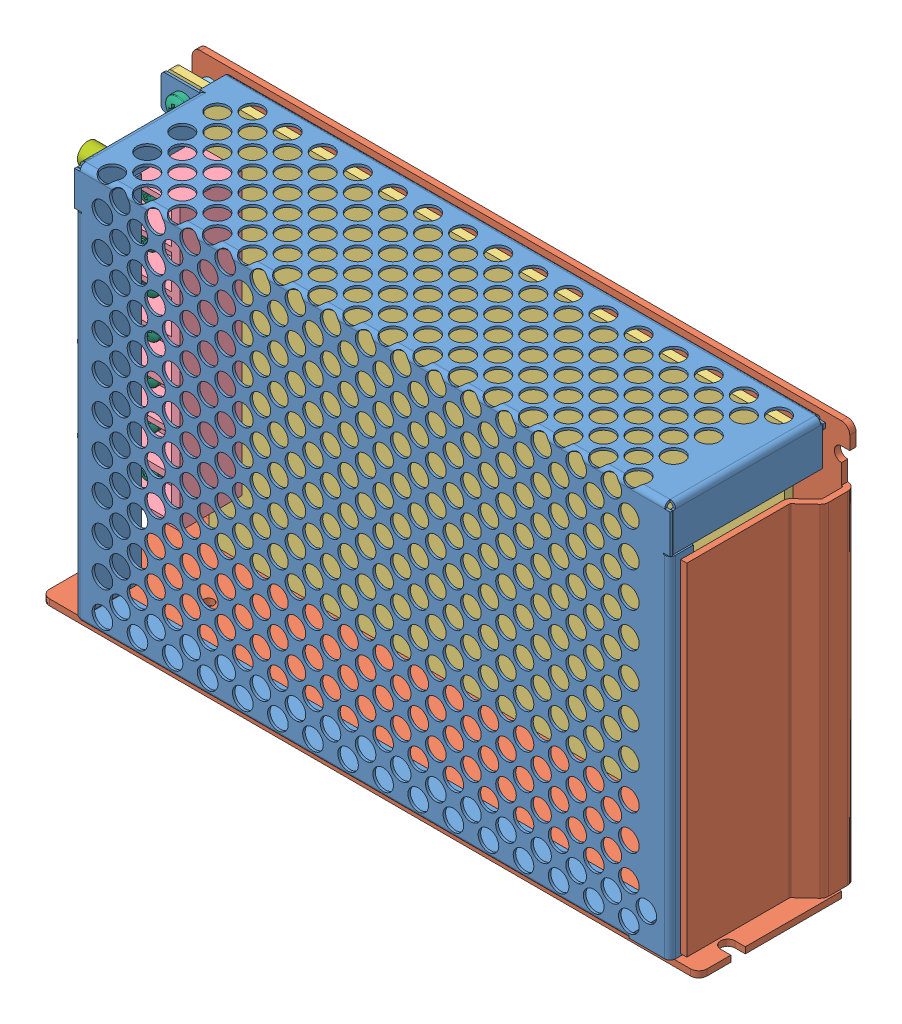
SolidWorks assembly MeanWell_RS-100, configuration Default. Lengths in mm.
Overall size (168.18 98 39.02).
18 component instances, 10 part files, 22 mates.
Components (placement in the parent):
- GRATE^MeanWell_RS-100-1: GRATE^MeanWell_RS-100 [Default] at (81.1 67.5 38.4225) x (0 1 0) z (1 0 0) size (95.52 37.52 154) (virtual)
- PLATE^MeanWell_RS-100-1: PLATE^MeanWell_RS-100 [Default] at origin size (159 98 38) (virtual)
- PCB^MeanWell_RS-100-1: PCB^MeanWell_RS-100 [Default] at (1.2532 0 0) size (149.23 94.42 2) (virtual)
- BLOCK^MeanWell_RS-100-1: BLOCK^MeanWell_RS-100 [Default] at (1.2532 0 0) size (18 68.05 15) (virtual)
- Part5^MeanWell_RS-100-1: Part5^MeanWell_RS-100 [Default] at (0 0 1.5) size (5 5 4) (virtual)
- pan head cross recess screw_iso-1: pan head cross recess screw_iso [ISO 7045 - M3 x 8 - Z - 8N] at (4.5 91 10.5) x (0 0 -1) z (0.977005 0.213215 0) size (10.35 5.6 5.6)
- pan head cross recess screw_iso-2: pan head cross recess screw_iso [ISO 7045 - M3 x 8 - Z - 8N] at (5.9804 78.9388 19.0526) x (0 0 -1) z (0.977005 0.213215 0) size (10.35 5.6 5.6)
- pan head cross recess screw_iso-3: pan head cross recess screw_iso [ISO 7045 - M3 x 8 - Z - 8N] at (5.9804 69.2602 19.1612) x (0 0 -1) z (0.977005 0.213215 0) size (10.35 5.6 5.6)
- pan head cross recess screw_iso-4: pan head cross recess screw_iso [ISO 7045 - M3 x 8 - Z - 8N] at (6.1839 59.8468 19.2114) x (0 0 -1) z (0.977005 0.213215 0) size (10.35 5.6 5.6)
- pan head cross recess screw_iso-5: pan head cross recess screw_iso [ISO 7045 - M3 x 8 - Z - 8N] at (6.1839 50.4574 19.0585) x (0 0 -1) z (0.977005 0.213215 0) size (10.35 5.6 5.6)
- pan head cross recess screw_iso-6: pan head cross recess screw_iso [ISO 7045 - M3 x 8 - Z - 8N] at (6.0089 40.8687 19.1627) x (0 0 -1) z (0.977005 0.213215 0) size (10.35 5.6 5.6)
- pan head cross recess screw_iso-7: pan head cross recess screw_iso [ISO 7045 - M3 x 8 - Z - 8N] at (6.0094 31.4444 19.1501) x (0 0 -1) z (0.977005 0.213215 0) size (10.35 5.6 5.6)
- pan head cross recess screw_iso-8: pan head cross recess screw_iso [ISO 7045 - M3 x 8 - Z - 8N] at (6.0094 21.1124 19.2488) x (0 0 -1) z (0.977005 0.213215 0) size (10.35 5.6 5.6)
- Insulated Ring Terminal ID 3mm-Red-11: Insulated Ring Terminal ID 3mm-Red [Black] at (5.9804 78.9388 15.75) x (0.000176 1 0) z (1 -0.000176 0) size (5.54 5.16 17.93)
- Insulated Ring Terminal ID 3mm-White-7: Insulated Ring Terminal ID 3mm-White [Default] at (5.9804 69.2602 15.75) x (0.000176 1 0) z (1 -0.000176 0) size (5.54 5.16 17.93) (hidden)
- Insulated Ring Terminal ID 3mm-Green-8: Insulated Ring Terminal ID 3mm-Green [Default] at (6.1839 59.8468 15.75) x (0.000176 1 0) z (1 -0.000176 0) size (5.54 5.16 31.83)
- Insulated Ring Terminal ID 3mm-9: Insulated Ring Terminal ID 3mm [Default] at (6.0089 40.8687 15.75) x (0.000176 1 0) z (1 -0.000176 0) size (5.54 5.16 17.93)
- Insulated Ring Terminal ID 3mm-Red-10: Insulated Ring Terminal ID 3mm-Red [Black] at (6.0094 21.1124 15.75) x (0.000176 1 0) z (1 -0.000176 0) size (5.54 5.16 17.93)
Mates (geometry in assembly coordinates):
- Coincident2: coincident anti-aligned: plane of Copy of GRATE^MeanWell_RS-100-1 through (122.644 95.1725 1.5) normal (0 0 -1); plane of PLATE-1 through (156.5 84.5 1.5) normal (0 0 1)
- Coincident3: coincident anti-aligned: plane of Copy of GRATE^MeanWell_RS-100-1 through (153.1 43.7612 35.5542) normal (1 0 0); plane of PLATE-1 through (153.1 2.5 12.0158) normal (-1 0 0)
- Coincident4: coincident anti-aligned: plane of Copy of GRATE^MeanWell_RS-100-1 through (117.644 1.5 33.3725) normal (0 -1 0); plane of PLATE-1 through (78.25 1.5 -47.7633) normal (0 1 0)
- Coincident5: coincident aligned: plane of Copy of PCB^MeanWell_RS-100-1 through (0.0262 59.5225 13.5) normal (-1 0 0); plane of BLOCK-1 through (0.0262 59.5225 13.5) normal (-1 0 0)
- Coincident6: coincident anti-aligned: plane of Copy of GRATE^MeanWell_RS-100-1 through (3.7317 91.5542 7.5) normal (0 0 -1); plane of PCB-1 through (95.6262 49.2125 7.5) normal (0 0 1)
- InPlace1: in place: plane of PLATE^MeanWell_RS-100-1 through (156.5 84.5 1.5) normal (0 0 1); plane of Part5^MeanWell_RS-100-1 through (0 0 1.5) normal (0 0 1); moOrthogonalPlaneRef_w of PLATE^MeanWell_RS-100-1 through (156.5 84.5 1.5) normal (0 0 1); plane of Part5^MeanWell_RS-100-1 through (0 0 1.5) normal (0 1 0); plane of PLATE^MeanWell_RS-100-1 through (156.5 84.5 1.5) normal (0 0 1); plane of Part5^MeanWell_RS-100-1 through (0 0 1.5) normal (1 0 0); plane of PLATE^MeanWell_RS-100-1 through (156.5 84.5 1.5) normal (0 0 1); unknown of Part5^MeanWell_RS-100-1
- Coincident7: coincident aligned: plane of ?; plane of ?
- Coincident8: coincident aligned: moOrthogonalPlaneRef_w of Copy of PLATE^MeanWell_RS-100-1 through (0 0 1.5) normal (0 1 0); plane of Part5^MeanWell_RS-100-1 through (0 0 1.5) normal (0 1 0)
- Coincident9: coincident anti-aligned: moOrthogonalPlaneRef_w of Copy of PLATE^MeanWell_RS-100-1 through (0 0 1.5) normal (-1 0 0); plane of Part5^MeanWell_RS-100-1 through (0 0 1.5) normal (1 0 0)
- Concentric1: concentric anti-aligned: cylinder of Part5^MeanWell_RS-100-1 through (4.5 91 5.5) axis (0 0 -1) radius 2.5; cylinder of pan head cross recess screw_iso-1 through (4.5 91 35.9) axis (0 0 1) radius 1.5
- Coincident10: coincident anti-aligned: plane of Copy of GRATE^MeanWell_RS-100-1 through (3.7317 91.5542 8.1) normal (0 0 1); plane of pan head cross recess screw_iso-1 through (4.1802 92.4655 8.1) normal (0 0 -1)
- Coincident11: coincident anti-aligned: plane of ? through (8.0262 78.5975 15.75) normal (0 0 1); plane of ? through (-4.0516 78.8869 15.75) normal (0 0 -1)
- Coincident12: coincident anti-aligned: plane of Copy of BLOCK^MeanWell_RS-100-1 through (8.0262 69.1475 15.75) normal (0 0 1); plane of Insulated Ring Terminal ID 3mm-Red-11 through (8.8673 76.0572 15.75) normal (0 0 -1)
- Concentric2: concentric aligned: cylinder of pan head cross recess screw_iso-2 through (5.9804 78.9388 44.4526) axis (0 0 1) radius 1.5; cylinder of Insulated Ring Terminal ID 3mm-Red-11 through (5.9804 78.9388 15.75) axis (0 0 1) radius 1.8415
- Coincident14: coincident anti-aligned: plane of Copy of BLOCK^MeanWell_RS-100-1 through (8.0262 69.1475 15.75) normal (0 0 1); plane of Insulated Ring Terminal ID 3mm-White-7 through (8.8673 66.3785 15.75) normal (0 0 -1)
- Coincident15: coincident anti-aligned: plane of Copy of BLOCK^MeanWell_RS-100-1 through (8.0262 59.6975 15.75) normal (0 0 1); plane of Insulated Ring Terminal ID 3mm-Green-8 through (9.0709 56.9652 15.75) normal (0 0 -1)
- Coincident16: coincident anti-aligned: plane of Copy of BLOCK^MeanWell_RS-100-1 through (8.0262 40.7975 15.75) normal (0 0 1); plane of Insulated Ring Terminal ID 3mm-9 through (8.8959 37.9871 15.75) normal (0 0 -1)
- Concentric3: concentric aligned: cylinder of pan head cross recess screw_iso-6 through (6.0089 40.8687 44.5627) axis (0 0 1) radius 1.5; cylinder of Insulated Ring Terminal ID 3mm-9 through (6.0089 40.8687 15.75) axis (0 0 1) radius 1.8415
- Concentric4: concentric aligned: cylinder of pan head cross recess screw_iso-4 through (6.1839 59.8468 44.6114) axis (0 0 1) radius 1.5; cylinder of Insulated Ring Terminal ID 3mm-Green-8 through (6.1839 59.8468 15.75) axis (0 0 1) radius 1.8415
- Concentric5: concentric aligned: cylinder of pan head cross recess screw_iso-3 through (5.9804 69.2602 44.5612) axis (0 0 1) radius 1.5; cylinder of Insulated Ring Terminal ID 3mm-White-7 through (5.9804 69.2602 15.75) axis (0 0 1) radius 1.8415
- Coincident17: coincident anti-aligned: plane of Copy of BLOCK^MeanWell_RS-100-1 through (8.0262 21.1725 15.75) normal (0 0 1); plane of Insulated Ring Terminal ID 3mm-Red-10 through (8.8963 18.2308 15.75) normal (0 0 -1)
- Concentric6: concentric aligned: cylinder of pan head cross recess screw_iso-8 through (6.0094 21.1124 44.6488) axis (0 0 1) radius 1.5; cylinder of Insulated Ring Terminal ID 3mm-Red-10 through (6.0094 21.1124 15.75) axis (0 0 1) radius 1.8415
